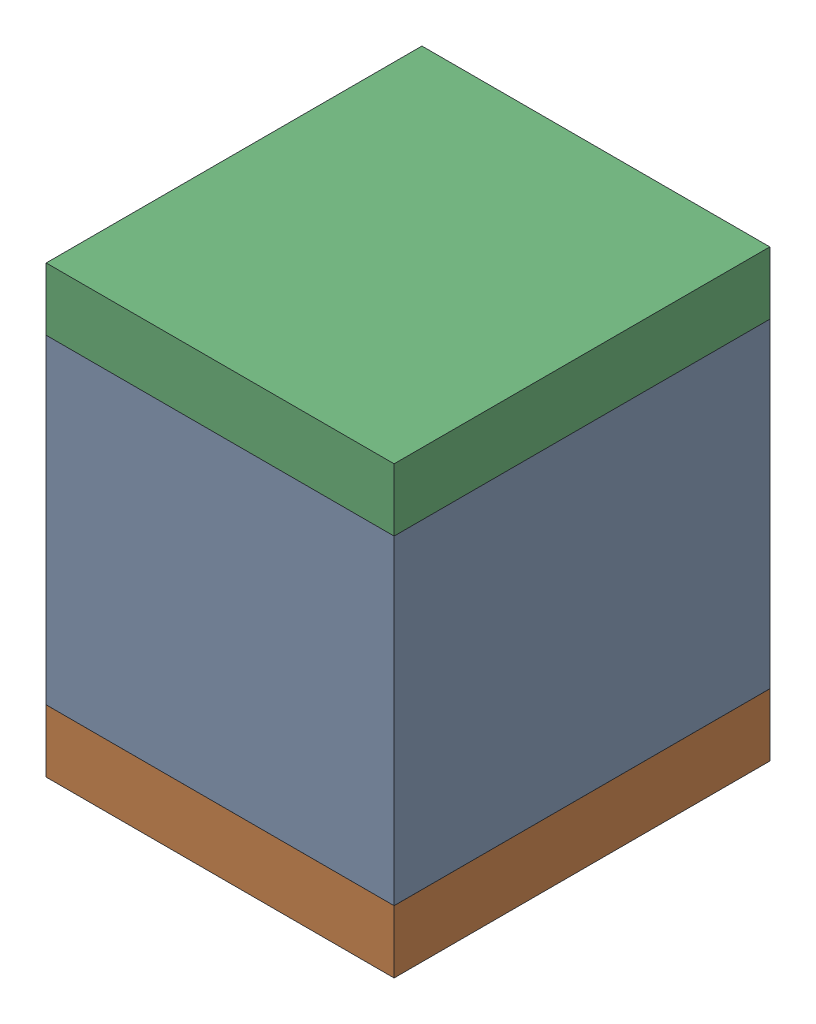
SolidWorks assembly C16, configuration ﾃﾞﾌｫﾙﾄ. Lengths in mm.
Overall size (2.5 3.2 2.7).
6 component instances, 2 part files, 0 mates.
Components (placement in the parent):
- 689260016-1: 689260016 [ﾃﾞﾌｫﾙﾄ] at (54.25 58.5 0) size (2.5 2.3 2.7)
  - Extruded_6-1: Extruded_6 [ﾃﾞﾌｫﾙﾄ] at origin size (2.5 2.3 2.7)
- 689260152-1: 689260152 [ﾃﾞﾌｫﾙﾄ] at (54.2501 57.125 0) size (2.5 0.45 2.7)
  - Extruded_7-1: Extruded_7 [ﾃﾞﾌｫﾙﾄ] at origin size (2.5 0.45 2.7)
- 689260152-2: 689260152 [ﾃﾞﾌｫﾙﾄ] at (54.2501 59.875 0) size (2.5 0.45 2.7)
  - Extruded_7-1: Extruded_7 [ﾃﾞﾌｫﾙﾄ] at origin size (2.5 0.45 2.7)
